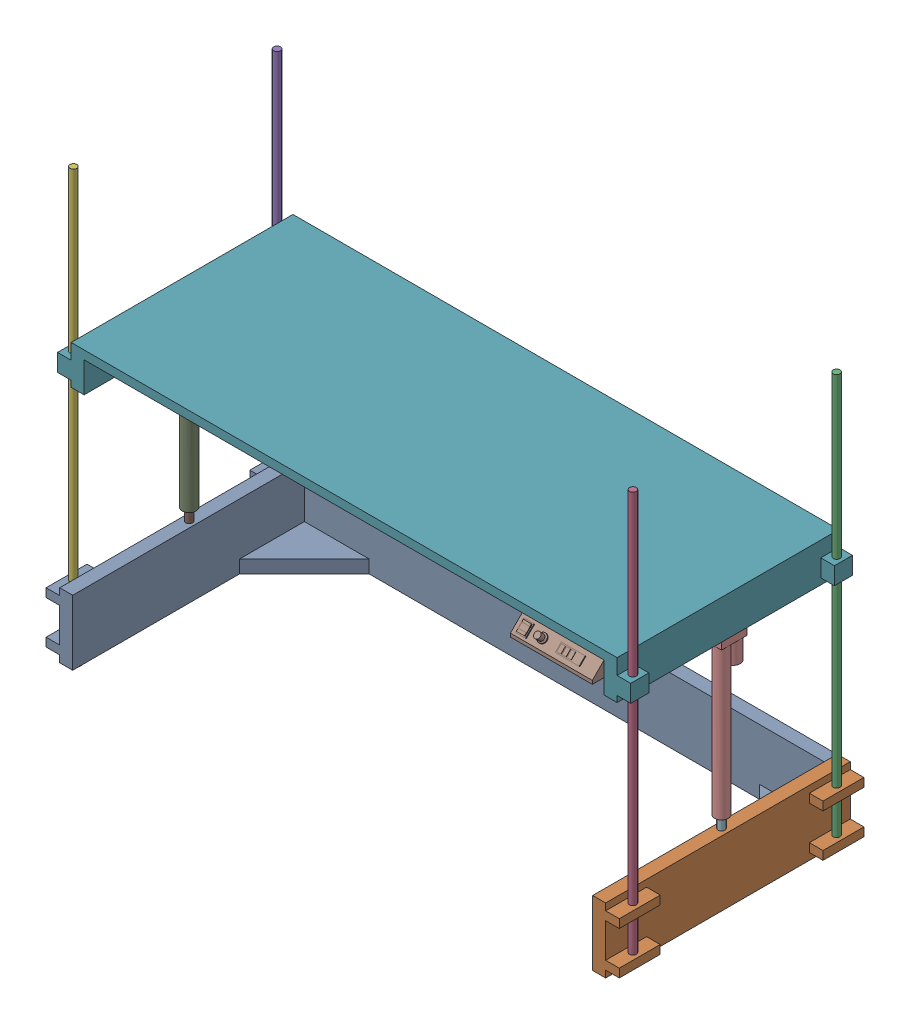
SolidWorks assembly Assem1, configuration Default. Lengths in mm.
Overall size (1680 1225 723.41).
13 component instances, 7 part files, 30 mates.
Components (placement in the parent):
- Leg Base Right-1: Leg Base Right [Default] at (550.8498 -56.0166 -252.6191) size (78 195.5 717)
- Leg Base Right-2: Leg Base Right [Default] at (2153.9303 -56.0166 470.5421) x (-1 0 0) z (0 0 -1) size (78 195.5 717)
- 1200x20mm rod-1: 1200x20mm rod [Default] at (2172.3901 -36.0166 -189.5385) size (20 1200 20)
- 1200x20mm rod-2: 1200x20mm rod [Default] at (2172.3901 -36.0166 407.4615) size (20 1200 20)
- 1200x20mm rod-3: 1200x20mm rod [Default] at (532.3901 -36.0166 -189.5385) size (20 1200 20)
- 1200x20mm rod-4: 1200x20mm rod [Default] at (532.3901 -36.0166 407.4615) size (20 1200 20)
- tabletop-2: tabletop [Default] at (552.3901 715.3471 -216.0385) size (1680 114 650)
- controller example-1: controller example [Default] at (1874.3901 670.808 401.7422) size (240 49.88 165.37)
- piston outer-3: piston outer [Default] at (572.3901 626.3471 107.9615) x (0 0 -1) z (-1 0 0) size (75 457 40)
- piston outer-4: piston outer [Default] at (2132.3901 626.3471 107.9615) x (0 0 -1) z (-1 0 0) size (75 457 40)
- piston inner-3: piston inner [Default] at (572.3901 134.4834 107.9615) x (0.974263 0 0.225414) z (-0.225414 0 0.974263) size (20 457 20)
- piston inner-4: piston inner [Default] at (2132.3901 134.4834 107.9615) x (-0.355896 0 -0.934526) z (0.934526 0 -0.355896) size (20 457 20)
- crossbar-1: crossbar [Default] at (590.3901 38.9834 -230.5385) size (1524 190 228)
Mates (geometry in assembly coordinates):
- Parallel1: parallel aligned: plane of Leg Base Right-1 through (550.8498 134.4834 -252.6191) normal (0 1 0); plane of Leg Base Right-2 through (2153.9303 134.4834 470.5421) normal (0 1 0)
- Concentric1: concentric anti-aligned: cylinder of Leg Base Right-2 through (2172.3901 -391.5166 407.4615) axis (0 1 0) radius 10; cylinder of 1200x20mm rod-2 through (2172.3901 1163.9834 407.4615) axis (0 -1 0) radius 10
- Coincident2: coincident aligned: plane of Leg Base Right-2 through (2192.3901 -36.0166 467.4615) normal (0 -1 0); plane of 1200x20mm rod-2 through (2172.3901 -36.0166 407.4615) normal (0 -1 0)
- Concentric2: concentric anti-aligned: cylinder of Leg Base Right-2 through (2172.3901 -391.5166 -189.5385) axis (0 1 0) radius 10; cylinder of 1200x20mm rod-1 through (2172.3901 1163.9834 -189.5385) axis (0 -1 0) radius 10
- Coincident3: coincident aligned: plane of Leg Base Right-2 through (2192.3901 -36.0166 -249.5385) normal (0 -1 0); plane of 1200x20mm rod-1 through (2172.3901 -36.0166 -189.5385) normal (0 -1 0)
- Concentric3: concentric anti-aligned: cylinder of Leg Base Right-1 through (532.3901 -391.5166 407.4615) axis (0 1 0) radius 10; cylinder of 1200x20mm rod-4 through (532.3901 1163.9834 407.4615) axis (0 -1 0) radius 10
- Coincident4: coincident aligned: plane of Leg Base Right-1 through (512.3901 -36.0166 467.4615) normal (0 -1 0); plane of 1200x20mm rod-4 through (532.3901 -36.0166 407.4615) normal (0 -1 0)
- Concentric4: concentric anti-aligned: cylinder of Leg Base Right-1 through (532.3901 -391.5166 -189.5385) axis (0 1 0) radius 10; cylinder of 1200x20mm rod-3 through (532.3901 1163.9834 -189.5385) axis (0 -1 0) radius 10
- Coincident5: coincident aligned: plane of Leg Base Right-1 through (512.3901 -36.0166 -249.5385) normal (0 -1 0); plane of 1200x20mm rod-3 through (532.3901 -36.0166 -189.5385) normal (0 -1 0)
- Concentric9: concentric aligned: cylinder of 1200x20mm rod-3 through (532.3901 1163.9834 -189.5385) axis (0 -1 0) radius 10; cylinder of tabletop-2 through (532.3901 773.3471 -189.5385) axis (0 -1 0) radius 10
- Concentric11: concentric aligned: cylinder of 1200x20mm rod-1 through (2172.3901 1163.9834 -189.5385) axis (0 -1 0) radius 10; cylinder of tabletop-2 through (2172.3901 773.3471 -189.5385) axis (0 -1 0) radius 10
- Concentric12: concentric aligned: cylinder of 1200x20mm rod-2 through (2172.3901 1163.9834 407.4615) axis (0 -1 0) radius 10; cylinder of tabletop-2 through (2172.3901 773.3471 407.4615) axis (0 -1 0) radius 10
- Concentric13: concentric aligned: cylinder of 1200x20mm rod-4 through (532.3901 1163.9834 407.4615) axis (0 -1 0) radius 10; cylinder of tabletop-2 through (532.3901 773.3471 407.4615) axis (0 -1 0) radius 10
- Coincident15: coincident aligned: plane of Leg Base Right-1 through (550.8498 -56.0166 -252.6191) normal (0 -1 0); plane of Leg Base Right-2 through (2153.9303 -56.0166 470.5421) normal (0 -1 0)
- Coincident16: coincident anti-aligned: plane of tabletop-2 through (552.3901 715.3471 -216.0385) normal (0 -1 0); plane of controller example-1 through (2114.3901 715.3471 433.9615) normal (0 1 0)
- Coincident17: coincident anti-aligned: plane of tabletop-2 through (2114.3901 626.3471 -216.0385) normal (-1 0 0); plane of controller example-1 through (2114.3901 670.808 401.7422) normal (1 0 0)
- Coincident18: coincident anti-aligned: line of tabletop-2 through (590.3901 715.3471 433.9615) axis (1 0 0); line of controller example-1 through (2114.3901 715.3471 433.9615) axis (-1 0 0)
- Coincident19: coincident anti-aligned: plane of tabletop-2 through (552.3901 626.3471 -216.0385) normal (0 -1 0); plane of piston outer-3 through (572.3901 626.3471 107.9615) normal (0 1 0)
- Coincident20: coincident aligned: plane of tabletop-2 through (552.3901 740.3471 -216.0385) normal (-1 0 0); plane of piston outer-3 through (552.3901 606.3471 127.9615) normal (-1 0 0)
- Coincident21: coincident aligned: plane of tabletop-2 through (552.3901 626.3471 127.9615) normal (0 0 1); plane of piston outer-3 through (552.3901 606.3471 127.9615) normal (0 0 1)
- Coincident22: coincident anti-aligned: plane of tabletop-2 through (552.3901 626.3471 -216.0385) normal (0 -1 0); plane of piston outer-4 through (2132.3901 626.3471 107.9615) normal (0 1 0)
- Coincident23: coincident aligned: plane of tabletop-2 through (2152.3901 740.3471 -216.0385) normal (1 0 0); plane of piston outer-4 through (2152.3901 606.3471 127.9615) normal (1 0 0)
- Coincident24: coincident aligned: plane of tabletop-2 through (552.3901 626.3471 127.9615) normal (0 0 1); plane of piston outer-4 through (2112.3901 606.3471 127.9615) normal (0 0 1)
- Concentric16: concentric aligned: cylinder of piston outer-4 through (2132.3901 695.3471 107.9615) axis (0 -1 0) radius 10; cylinder of piston inner-4 through (2132.3901 591.4834 107.9615) axis (0 -1 0) radius 10
- Concentric17: concentric aligned: cylinder of piston outer-3 through (572.3901 695.3471 107.9615) axis (0 -1 0) radius 10; cylinder of piston inner-3 through (572.3901 591.4834 107.9615) axis (0 -1 0) radius 10
- Coincident25: coincident anti-aligned: plane of Leg Base Right-1 through (550.8498 134.4834 -252.6191) normal (0 1 0); plane of piston inner-3 through (572.3901 134.4834 107.9615) normal (0 -1 0)
- Coincident26: coincident anti-aligned: plane of Leg Base Right-2 through (2153.9303 134.4834 470.5421) normal (0 1 0); plane of piston inner-4 through (2132.3901 134.4834 107.9615) normal (0 -1 0)
- Coincident27: coincident anti-aligned: plane of Leg Base Right-1 through (590.3901 134.4834 -249.5385) normal (1 0 0); plane of crossbar-1 through (590.3901 38.9834 -230.5385) normal (-1 0 0)
- Coincident28: coincident aligned: plane of Leg Base Right-1 through (552.3901 134.4834 -249.5385) normal (0 0 -1); plane of crossbar-1 through (2114.3901 133.9834 -249.5385) normal (0 0 -1)
- Coincident29: coincident aligned: plane of Leg Base Right-1 through (550.8498 -56.0166 -252.6191) normal (0 -1 0); plane of crossbar-1 through (2114.3901 -56.0166 -211.5385) normal (0 -1 0)
